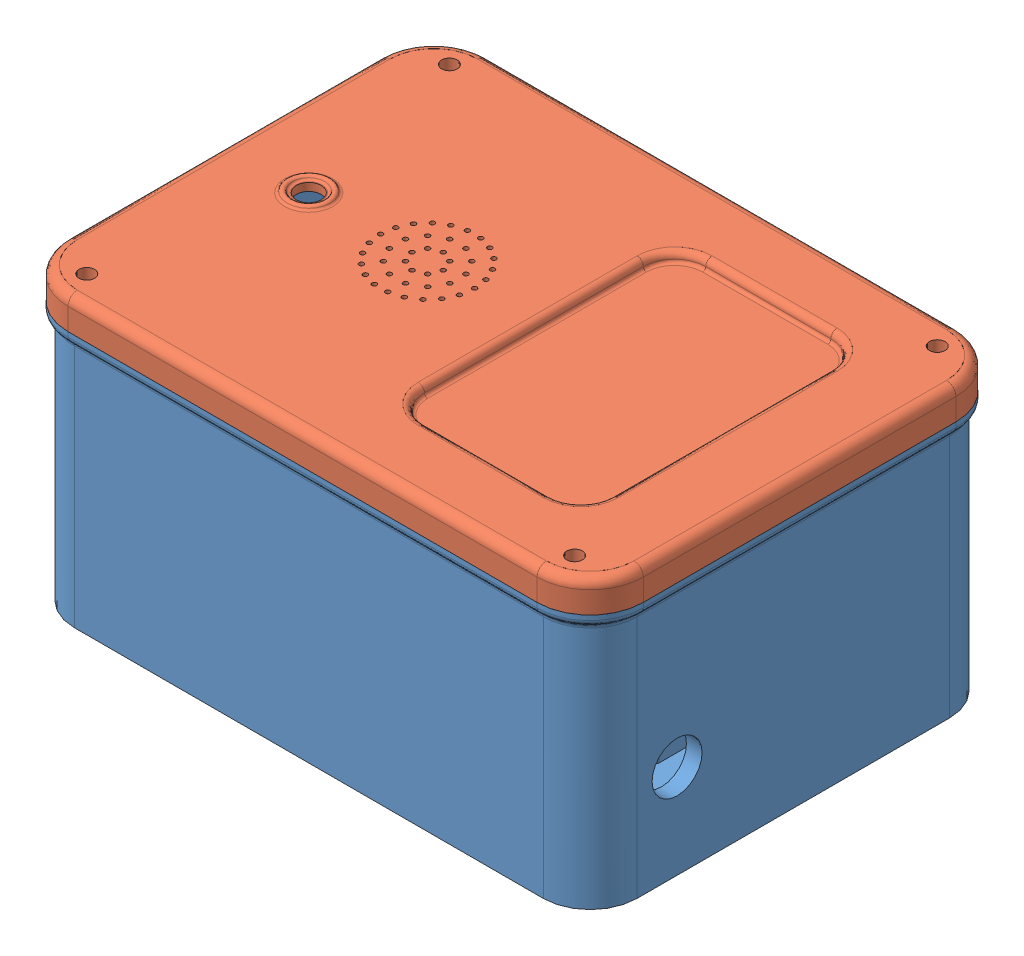
SolidWorks assembly Ensamblaje1, configuration Predeterminado. Lengths in mm.
Overall size (184 94 134).
2 component instances, 2 part files, 4 mates.
Components (placement in the parent):
- Caja electrónica-1: Caja electrónica [Predeterminado] at (18.0536 -48.7234 189.0647) size (184 86 134)
- Tapa caja-1: Tapa caja [Predeterminado] at (18.0536 34.2766 189.0647) size (184 11 134)
Mates (geometry in assembly coordinates):
- Coincidente1: coincident: plane of Caja electrónica-1 through (-56.9464 37.2766 256.0647) normal (0 0 1); plane of Tapa caja-1 through (-56.9464 44.2766 256.0647) normal (0 0 1)
- Coincidente2: coincident: plane of Caja electrónica-1 through (-56.9464 37.2766 256.0647) normal (0 0 1); plane of Tapa caja-1 through (-56.9464 44.2766 256.0647) normal (0 0 1)
- Coincidente3: coincident: plane of Caja electrónica-1 through (-73.9464 37.2766 139.0647) normal (-1 0 0); plane of Tapa caja-1 through (-73.9464 44.2766 239.0647) normal (-1 0 0)
- Coincidente4: coincident: plane of Caja electrónica-1 through (93.0536 34.2766 139.0647) normal (0 1 0); plane of Tapa caja-1 through (93.0536 34.2766 139.0647) normal (0 -1 0)
